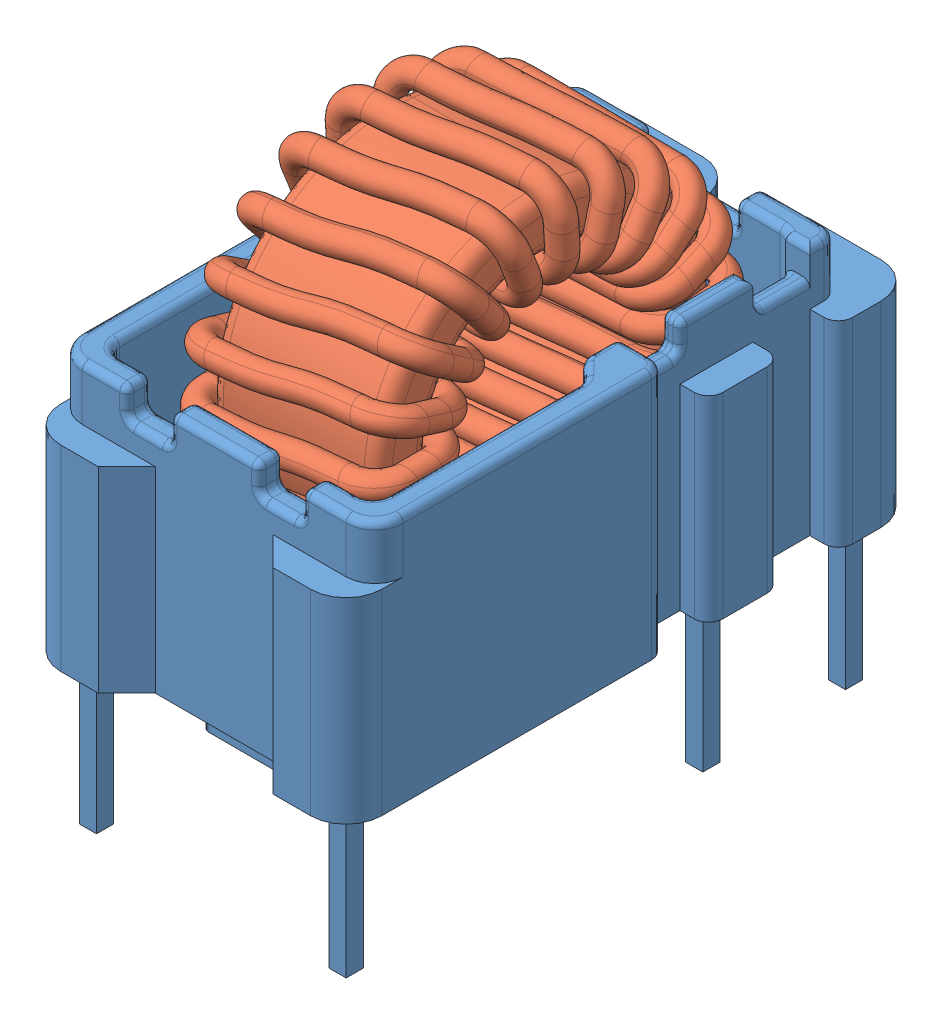
SolidWorks assembly P0584, configuration Default. Lengths in mm.
Overall size (11.43 21.02 20.32).
3 component instances, 2 part files, 0 mates.
Components (placement in the parent):
- P0584.STEP-1: P0584.STEP [Default] at origin size (11.43 21.02 20.32)
  - 043-2383.STEP-1: 043-2383.STEP [Default] at (2.5751 -5.2354 30.48) size (11.43 14.23 20.32)
  - 032-P0584.STEP-1: 032-P0584.STEP [Default] at (2.5751 2.1962 20.6408) x (0 -0.125696 -0.992069) z (0 -0.992069 0.125696) size (14.09 8.79 14.46)
